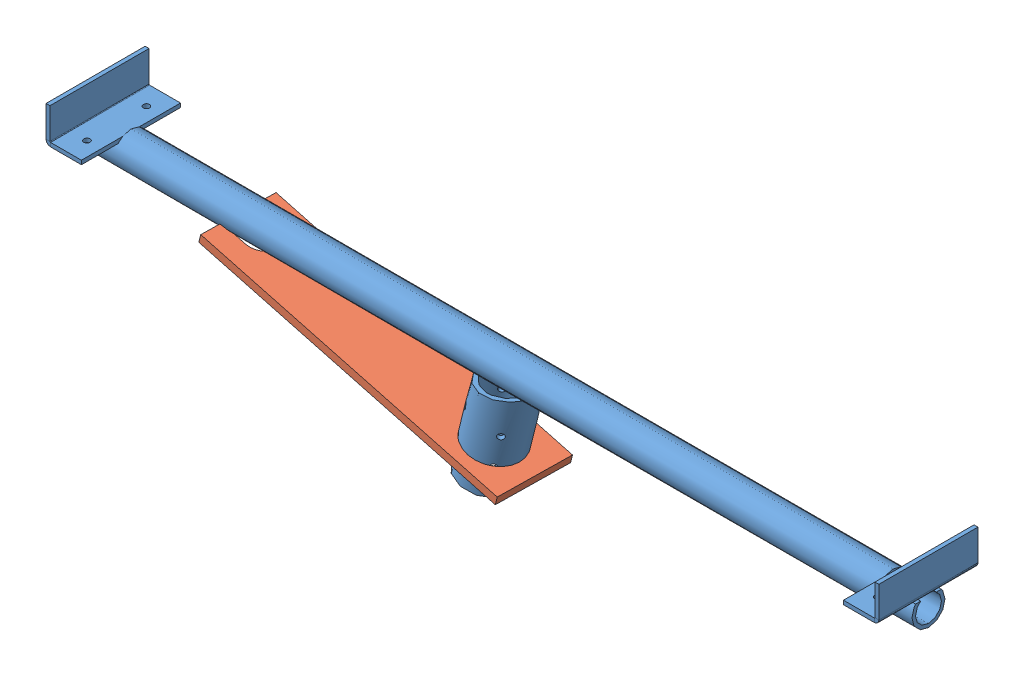
SolidWorks assembly Assem2, configuration Default. Lengths in mm.
Overall size (672.2 124.49 80).
2 component instances, 2 part files, 2 mates.
Components (placement in the parent):
- Across Mount-1: Across Mount [Default<As Machined>] at (159.6287 401.3597 546.996) size (672.2 124.49 80)
- Part1-1: Part1 [Default] at (143.7623 337.7232 546.996) x (0.970211 -0.241901 0.013187) z (-0.012795 0.00319 0.999913) size (250 6.35 60)
Mates (geometry in assembly coordinates):
- Concentric1: concentric: cylinder of Across Mount-1 through (125.6889 265.2348 546.996) axis (0.241922 0.970296 0) radius 21.082; cylinder of Part1-1 through (143.7262 337.5783 546.996) axis (-0.241922 -0.970296 0) radius 21.1
- Coincident1: coincident: line of Across Mount-1 through (124.8427 348.9848 546.996) axis (-0.970296 0.241922 0); plane of Part1-1 through (-24.1974 386.1447 544.6923) normal (0.241922 0.970296 0)
